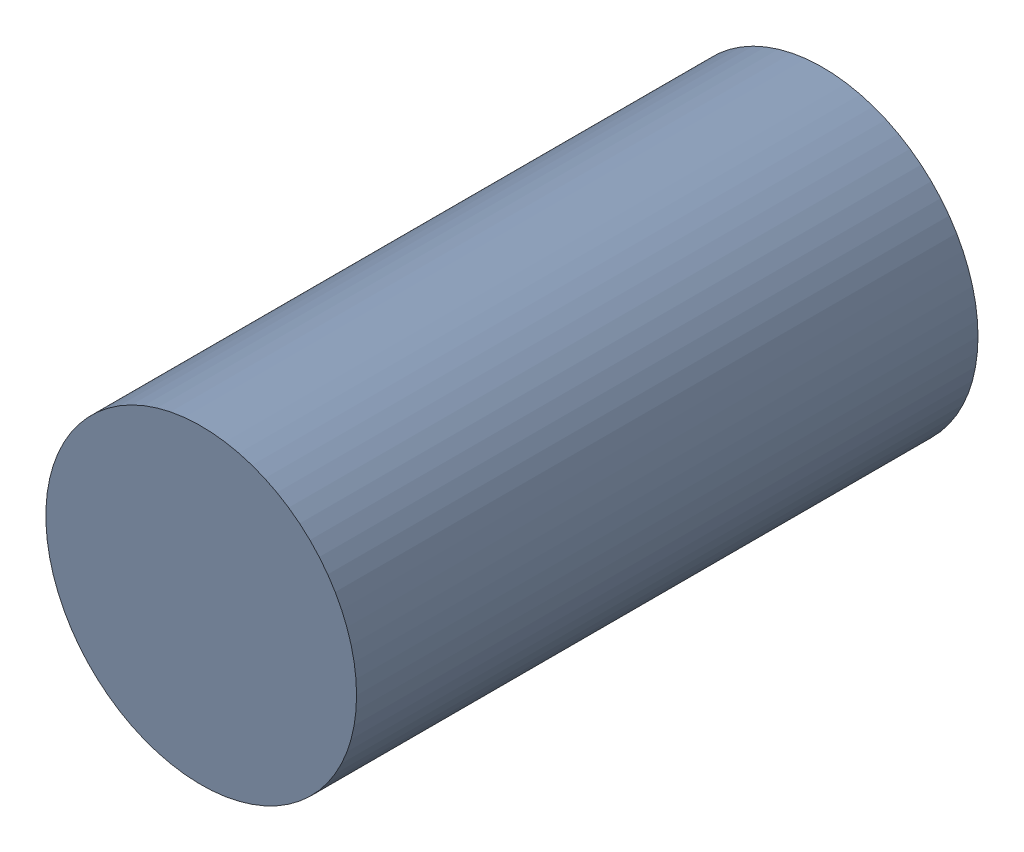
SolidWorks assembly MH8_1.step, configuration Default. Lengths in mm.
Overall size (1 1 2).
2 component instances, 1 part files, 0 mates.
Components (placement in the parent):
- 9228463120_1.step-3: 9228463120_1.step [Default] at (453.1617 244.3607 -1.5) size (1 1 2)
  - Cylinder_1.step-26: Cylinder_1.step [Default] at origin size (1 1 2)
